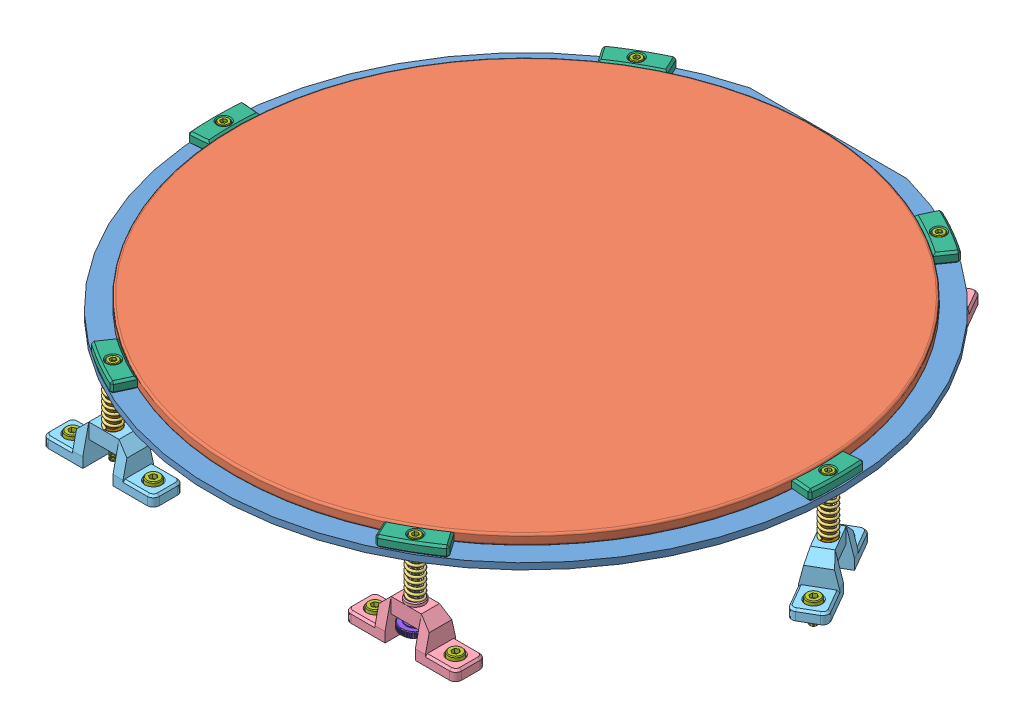
SolidWorks assembly Bed Assembly, configuration Default. Lengths in mm.
Overall size (340.49 52.35 312.47).
44 component instances, 9 part files, 98 mates.
Components (placement in the parent):
- Heat Bed-1: Heat Bed [Default] at origin size (310 3.1 305.01)
- Print Surface-1: Print Surface [Default] at (0 3.1 0) size (290 5.25 290)
- Bed Leveling Spring-1: Bed Leveling Spring [Default] at (150 -20 0) size (8.52 22.05 8.3)
- Bed Leveling Spring-2: Bed Leveling Spring [Default] at (75 -20 129.9038) size (8.52 22.05 8.3)
- Bed Leveling Spring-3: Bed Leveling Spring [Default] at (-75 -20 129.9038) size (8.52 22.05 8.3)
- Bed Leveling Spring-4: Bed Leveling Spring [Default] at (-150 -20 0) size (8.52 22.05 8.3)
- Bed Leveling Spring-5: Bed Leveling Spring [Default] at (-75 -20 -129.9038) size (8.52 22.05 8.3)
- Bed Leveling Spring-6: Bed Leveling Spring [Default] at (75 -20 -129.9038) size (8.52 22.05 8.3)
- Bed Foot-1: Bed Foot [Default] at (47.5 -38.5 122.4038) size (55 20.3 15)
- Bed Static Foot-2: Bed Static Foot [Default] at (-102.5 -38.5 122.4038) size (55 18.5 15)
- Bed Foot-3: Bed Foot [Default] at (82.2548 -38.5 -102.3381) x (-0.5 0 -0.866025) z (0.866025 0 -0.5) size (55 20.3 15)
- Bed Static Foot-4: Bed Static Foot [Default] at (-95.2452 -38.5 -109.8381) x (0.5 0 -0.866025) z (0.866025 0 0.5) size (55 18.5 15)
- Bed Foot-5: Bed Foot [Default] at (-170.2452 -38.5 20.0657) x (0.5 0 -0.866025) z (0.866025 0 0.5) size (55 20.3 15)
- Bed Static Foot-6: Bed Static Foot [Default] at (157.2548 -38.5 27.5657) x (-0.5 0 -0.866025) z (0.866025 0 -0.5) size (55 18.5 15)
- Print Surface Clip-1: Print Surface Clip [Default] at (0 3.1 0) x (0.866025 0 0.5) z (-0.5 0 0.866025) size (26.84 5.25 10.55)
- Print Surface Clip-2: Print Surface Clip [Default] at (0 3.1 0) x (0.866025 0 -0.5) z (0.5 0 0.866025) size (26.84 5.25 10.55)
- Print Surface Clip-3: Print Surface Clip [Default] at (0 3.1 0) x (0 0 -1) z (1 0 0) size (26.84 5.25 10.55)
- Print Surface Clip-4: Print Surface Clip [Default] at (0 3.1 0) x (-0.866025 0 -0.5) z (0.5 0 -0.866025) size (26.84 5.25 10.55)
- Print Surface Clip-5: Print Surface Clip [Default] at (0 3.1 0) x (-0.866025 0 0.5) z (-0.5 0 -0.866025) size (26.84 5.25 10.55)
- Print Surface Clip-6: Print Surface Clip [Default] at (0 3.1 0) x (0 0 1) z (-1 0 0) size (26.84 5.25 10.55)
- socket head cap screw_am-1: socket head cap screw_am [B18.3.1M - 3 x 0.5 x 40 Hex SHCS -- 40SHX] at (-150 8.35 0) x (0 -1 0) z (-0.546944 0 0.837169) size (43 5.5 5.5)
- socket head cap screw_am-2: socket head cap screw_am [B18.3.1M - 3 x 0.5 x 40 Hex SHCS -- 40SHX] at (-75 8.35 129.9038) x (0 -1 0) z (-0.546944 0 0.837169) size (43 5.5 5.5)
- socket head cap screw_am-3: socket head cap screw_am [B18.3.1M - 3 x 0.5 x 40 Hex SHCS -- 40SHX] at (75 8.35 129.9038) x (0 -1 0) z (-0.546944 0 0.837169) size (43 5.5 5.5)
- socket head cap screw_am-4: socket head cap screw_am [B18.3.1M - 3 x 0.5 x 40 Hex SHCS -- 40SHX] at (150 8.35 0) x (0 -1 0) z (-0.546944 0 0.837169) size (43 5.5 5.5)
- socket head cap screw_am-5: socket head cap screw_am [B18.3.1M - 3 x 0.5 x 40 Hex SHCS -- 40SHX] at (75 8.35 -129.9038) x (0 -1 0) z (-0.546944 0 0.837169) size (43 5.5 5.5)
- socket head cap screw_am-6: socket head cap screw_am [B18.3.1M - 3 x 0.5 x 40 Hex SHCS -- 40SHX] at (-75 8.35 -129.9038) x (0 -1 0) z (-0.546944 0 0.837169) size (43 5.5 5.5)
- Bed Leveling Knob-1: Bed Leveling Knob [Default] at (75 -32 129.9038) x (0 1 0) z (0 0 1) size (12 14 14)
- Bed Leveling Knob-3: Bed Leveling Knob [Default] at (75 -32 -129.9038) x (0 1 0) z (0 0 1) size (12 14 14)
- Bed Leveling Knob-5: Bed Leveling Knob [Default] at (-150 -32 0) x (0 1 0) z (0 0 1) size (12 14 14)
- socket head cap screw_am-7: socket head cap screw_am [B18.3.1M - 4 x 0.7 x 8 Hex SHCS -- 8SHX] at (-65 -32 -147.2243) x (0 -1 0) z (0 0 1) size (12 7 7)
- socket head cap screw_am-8: socket head cap screw_am [B18.3.1M - 4 x 0.7 x 8 Hex SHCS -- 8SHX] at (-85 -32 -112.5833) x (0 -1 0) z (-0.546944 0 0.837169) size (12 7 7)
- socket head cap screw_am-9: socket head cap screw_am [B18.3.1M - 4 x 0.7 x 8 Hex SHCS -- 8SHX] at (-140 -32 -17.3205) x (0 -1 0) z (-0.546944 0 0.837169) size (12 7 7)
- socket head cap screw_am-10: socket head cap screw_am [B18.3.1M - 4 x 0.7 x 8 Hex SHCS -- 8SHX] at (-160 -32 17.3205) x (0 -1 0) z (-0.546944 0 0.837169) size (12 7 7)
- socket head cap screw_am-11: socket head cap screw_am [B18.3.1M - 4 x 0.7 x 8 Hex SHCS -- 8SHX] at (65 -32 -147.2243) x (0 -1 0) z (-0.546944 0 0.837169) size (12 7 7)
- socket head cap screw_am-12: socket head cap screw_am [B18.3.1M - 4 x 0.7 x 8 Hex SHCS -- 8SHX] at (85 -32 -112.5833) x (0 -1 0) z (-0.546944 0 0.837169) size (12 7 7)
- socket head cap screw_am-13: socket head cap screw_am [B18.3.1M - 4 x 0.7 x 8 Hex SHCS -- 8SHX] at (140 -32 -17.3205) x (0 -1 0) z (-0.546944 0 0.837169) size (12 7 7)
- socket head cap screw_am-14: socket head cap screw_am [B18.3.1M - 4 x 0.7 x 8 Hex SHCS -- 8SHX] at (160 -32 17.3205) x (0 -1 0) z (-0.546944 0 0.837169) size (12 7 7)
- socket head cap screw_am-15: socket head cap screw_am [B18.3.1M - 4 x 0.7 x 8 Hex SHCS -- 8SHX] at (95 -32 129.9038) x (0 -1 0) z (-0.546944 0 0.837169) size (12 7 7)
- socket head cap screw_am-16: socket head cap screw_am [B18.3.1M - 4 x 0.7 x 8 Hex SHCS -- 8SHX] at (55 -32 129.9038) x (0 -1 0) z (-0.546944 0 0.837169) size (12 7 7)
- socket head cap screw_am-17: socket head cap screw_am [B18.3.1M - 4 x 0.7 x 8 Hex SHCS -- 8SHX] at (-55 -32 129.9038) x (0 -1 0) z (-0.546944 0 0.837169) size (12 7 7)
- socket head cap screw_am-18: socket head cap screw_am [B18.3.1M - 4 x 0.7 x 8 Hex SHCS -- 8SHX] at (-95 -32 129.9038) x (0 -1 0) z (-0.546944 0 0.837169) size (12 7 7)
- Surface Clip End Stop-1: Surface Clip End Stop [Default] at (-75 -28.5 -129.9038) size (7.7 20.5 7.7)
- Surface Clip End Stop-2: Surface Clip End Stop [Default] at (150 -28.5 0) size (7.7 20.5 7.7)
- Surface Clip End Stop-3: Surface Clip End Stop [Default] at (-75 -28.5 129.9038) size (7.7 20.5 7.7)
Mates (geometry in assembly coordinates):
- Coincident1: coincident: plane of Heat Bed-1 through (0 3.1 0) normal (0 1 0); plane of Print Surface-1 through (0 3.1 0) normal (0 -1 0)
- Concentric1: concentric: cylinder of Heat Bed-1 through (0 3.1 0) axis (0 -1 0) radius 155; cylinder of Print Surface-1 through (0 8.35 0) axis (0 -1 0) radius 145
- Concentric2: concentric: cylinder of Heat Bed-1 through (150 1.1 0) axis (0 1 0) radius 3.25; cylinder of Bed Leveling Spring-1 through (150 -21.2 0) axis (0 1 0) radius 2.95
- Concentric3: concentric: cylinder of Heat Bed-1 through (75 1.1 129.9038) axis (0 1 0) radius 3.25; cylinder of Bed Leveling Spring-2 through (75 -21.2 129.9038) axis (0 1 0) radius 2.95
- Concentric4: concentric: cylinder of Heat Bed-1 through (-75 1.1 129.9038) axis (0 1 0) radius 3.25; cylinder of Bed Leveling Spring-3 through (-75 -21.2 129.9038) axis (0 1 0) radius 2.95
- Concentric5: concentric: cylinder of Heat Bed-1 through (-150 1.1 0) axis (0 1 0) radius 3.25; cylinder of Bed Leveling Spring-4 through (-150 -21.2 0) axis (0 1 0) radius 2.95
- Concentric6: concentric: cylinder of Heat Bed-1 through (-75 1.1 -129.9038) axis (0 1 0) radius 3.25; cylinder of Bed Leveling Spring-5 through (-75 -21.2 -129.9038) axis (0 1 0) radius 2.95
- Concentric7: concentric: cylinder of Heat Bed-1 through (75 1.1 -129.9038) axis (0 1 0) radius 3.25; cylinder of Bed Leveling Spring-6 through (75 -21.2 -129.9038) axis (0 1 0) radius 2.95
- Coincident2: coincident: plane of Heat Bed-1 through (0 0 0) normal (0 -1 0); plane of Bed Leveling Spring-2 through (118 0 124.9038) normal (0 1 0)
- Coincident3: coincident: plane of Heat Bed-1 through (0 0 0) normal (0 -1 0); plane of Bed Leveling Spring-1 through (193 0 -5) normal (0 1 0)
- Coincident4: coincident: plane of Heat Bed-1 through (0 0 0) normal (0 -1 0); plane of Bed Leveling Spring-6 through (118 0 -134.9038) normal (0 1 0)
- Coincident5: coincident: plane of Heat Bed-1 through (0 0 0) normal (0 -1 0); plane of Bed Leveling Spring-5 through (-32 0 -134.9038) normal (0 1 0)
- Coincident6: coincident: plane of Heat Bed-1 through (0 0 0) normal (0 -1 0); plane of Bed Leveling Spring-4 through (-107 0 -5) normal (0 1 0)
- Coincident7: coincident: plane of Heat Bed-1 through (0 0 0) normal (0 -1 0); plane of Bed Leveling Spring-3 through (-32 0 124.9038) normal (0 1 0)
- Coincident8: coincident: plane of Bed Leveling Spring-1 through (107 -20 5) normal (0 -1 0); plane of Bed Static Foot-6 through (150.2452 -20 -14.5753) normal (0 1 0)
- Concentric8: concentric: cylinder of Bed Leveling Spring-1 through (150 -21.2 0) axis (0 1 0) radius 2.95; cylinder of Bed Static Foot-6 through (150 -39.8137 0) axis (0 1 0) radius 4
- Coincident9: coincident: plane of Bed Leveling Spring-4 through (-193 -20 5) normal (0 -1 0); plane of Bed Foot-5 through (-137.2548 -20 -7.0753) normal (0 1 0)
- Concentric9: concentric: cylinder of Bed Leveling Spring-4 through (-150 -21.2 0) axis (0 1 0) radius 2.95; cylinder of Bed Foot-5 through (-150 -37.6924 0) axis (0 1 0) radius 3.25
- Coincident12: coincident: plane of Bed Leveling Spring-2 through (32 -20 134.9038) normal (0 -1 0); plane of Bed Foot-1 through (87.5 -20 137.4038) normal (0 1 0)
- Concentric11: concentric: cylinder of Bed Leveling Spring-2 through (75 -21.2 129.9038) axis (0 1 0) radius 2.95; cylinder of Bed Foot-1 through (75 -37.6924 129.9038) axis (0 1 0) radius 3.25
- Coincident14: coincident: plane of Bed Leveling Spring-3 through (-118 -20 134.9038) normal (0 -1 0); plane of Bed Static Foot-2 through (-62.5 -20 137.4038) normal (0 1 0)
- Concentric10: concentric: cylinder of Bed Leveling Spring-3 through (-75 -21.2 129.9038) axis (0 1 0) radius 2.95; cylinder of Bed Static Foot-2 through (-75 -39.8137 129.9038) axis (0 1 0) radius 4
- Coincident18: coincident: plane of Bed Leveling Spring-6 through (32 -20 -124.9038) normal (0 -1 0); plane of Bed Foot-3 through (75.2452 -20 -144.4791) normal (0 1 0)
- Concentric12: concentric: cylinder of Bed Leveling Spring-6 through (75 -21.2 -129.9038) axis (0 1 0) radius 2.95; cylinder of Bed Foot-3 through (75 -37.6924 -129.9038) axis (0 1 0) radius 3.25
- Coincident20: coincident: plane of Bed Leveling Spring-5 through (-118 -20 -124.9038) normal (0 -1 0); plane of Bed Static Foot-4 through (-62.2548 -20 -136.9791) normal (0 1 0)
- Concentric13: concentric: cylinder of Bed Leveling Spring-5 through (-75 -21.2 -129.9038) axis (0 1 0) radius 2.95; cylinder of Bed Static Foot-4 through (-75 -39.8137 -129.9038) axis (0 1 0) radius 4
- Coincident23: coincident: plane of Bed Foot-1 through (47.5 -38.5 137.4038) normal (0 0 1); plane of Bed Static Foot-2 through (-102.5 -38.5 137.4038) normal (0 0 1)
- Coincident24: coincident: plane of Bed Foot-3 through (95.2452 -38.5 -109.8381) normal (0.866025 0 -0.5); plane of Bed Static Foot-6 through (170.2452 -38.5 20.0657) normal (0.866025 0 -0.5)
- Coincident25: coincident: plane of Bed Static Foot-4 through (-95.2452 -38.5 -109.8381) normal (-0.866025 0 -0.5); plane of Bed Foot-5 through (-170.2452 -38.5 20.0657) normal (-0.866025 0 -0.5)
- Concentric14: concentric: cylinder of Heat Bed-1 through (-75 1.1 129.9038) axis (0 1 0) radius 3.25; cylinder of Print Surface Clip-1 through (-75 5.35 129.9038) axis (0 1 0) radius 2.9
- Concentric15: concentric: cylinder of Heat Bed-1 through (75 1.1 129.9038) axis (0 1 0) radius 3.25; cylinder of Print Surface Clip-2 through (75 5.35 129.9038) axis (0 1 0) radius 2.9
- Concentric16: concentric: cylinder of Heat Bed-1 through (150 1.1 0) axis (0 1 0) radius 3.25; cylinder of Print Surface Clip-3 through (150 5.35 0) axis (0 1 0) radius 2.9
- Concentric17: concentric: cylinder of Heat Bed-1 through (75 1.1 -129.9038) axis (0 1 0) radius 3.25; cylinder of Print Surface Clip-4 through (75 5.35 -129.9038) axis (0 1 0) radius 2.9
- Concentric18: concentric: cylinder of Heat Bed-1 through (-75 1.1 -129.9038) axis (0 1 0) radius 3.25; cylinder of Print Surface Clip-5 through (-75 5.35 -129.9038) axis (0 1 0) radius 2.9
- Concentric19: concentric: cylinder of Heat Bed-1 through (-150 1.1 0) axis (0 1 0) radius 3.25; cylinder of Print Surface Clip-6 through (-150 5.35 0) axis (0 1 0) radius 2.9
- Coincident27: coincident: plane of Heat Bed-1 through (0 3.1 0) normal (0 1 0); plane of Print Surface Clip-1 through (0 3.1 0) normal (0 -1 0)
- Coincident28: coincident: plane of Heat Bed-1 through (0 3.1 0) normal (0 1 0); plane of Print Surface Clip-2 through (0 3.1 0) normal (0 -1 0)
- Coincident29: coincident: plane of Heat Bed-1 through (0 3.1 0) normal (0 1 0); plane of Print Surface Clip-3 through (0 3.1 0) normal (0 -1 0)
- Coincident30: coincident: plane of Heat Bed-1 through (0 3.1 0) normal (0 1 0); plane of Print Surface Clip-4 through (0 3.1 0) normal (0 -1 0)
- Coincident31: coincident: plane of Heat Bed-1 through (0 3.1 0) normal (0 1 0); plane of Print Surface Clip-5 through (0 3.1 0) normal (0 -1 0)
- Coincident32: coincident: plane of Heat Bed-1 through (0 3.1 0) normal (0 1 0); plane of Print Surface Clip-6 through (0 3.1 0) normal (0 -1 0)
- Concentric20: concentric: cylinder of Heat Bed-1 through (0 3.1 0) axis (0 -1 0) radius 155; cylinder of Print Surface Clip-2 through (0 8.35 0) axis (0 -1 0) radius 155
- Concentric21: concentric: cylinder of Heat Bed-1 through (0 3.1 0) axis (0 -1 0) radius 155; cylinder of Print Surface Clip-3 through (0 8.35 0) axis (0 -1 0) radius 155
- Concentric22: concentric: cylinder of Heat Bed-1 through (0 3.1 0) axis (0 -1 0) radius 155; cylinder of Print Surface Clip-4 through (0 8.35 0) axis (0 -1 0) radius 155
- Concentric23: concentric: cylinder of Heat Bed-1 through (0 3.1 0) axis (0 -1 0) radius 155; cylinder of Print Surface Clip-5 through (0 8.35 0) axis (0 -1 0) radius 155
- Concentric24: concentric: cylinder of Heat Bed-1 through (0 3.1 0) axis (0 -1 0) radius 155; cylinder of Print Surface Clip-6 through (0 8.35 0) axis (0 -1 0) radius 155
- Concentric25: concentric: cylinder of Heat Bed-1 through (0 3.1 0) axis (0 -1 0) radius 155; cylinder of Print Surface Clip-1 through (0 8.35 0) axis (0 -1 0) radius 155
- Concentric26: concentric: cylinder of Print Surface Clip-6 through (-150 5.35 0) axis (0 1 0) radius 2.9; cylinder of socket head cap screw_am-1 through (-150 40.1 0) axis (0 1 0) radius 2.75
- Concentric27: concentric: cylinder of Print Surface Clip-1 through (-75 5.35 129.9038) axis (0 1 0) radius 2.9; cylinder of socket head cap screw_am-2 through (-75 40.1 129.9038) axis (0 1 0) radius 2.75
- Concentric28: concentric: cylinder of Print Surface Clip-2 through (75 5.35 129.9038) axis (0 1 0) radius 2.9; cylinder of socket head cap screw_am-3 through (75 40.1 129.9038) axis (0 1 0) radius 2.75
- Concentric29: concentric: cylinder of Print Surface Clip-3 through (150 5.35 0) axis (0 1 0) radius 2.9; cylinder of socket head cap screw_am-4 through (150 40.1 0) axis (0 1 0) radius 2.75
- Concentric30: concentric: cylinder of Print Surface Clip-4 through (75 5.35 -129.9038) axis (0 1 0) radius 2.9; cylinder of socket head cap screw_am-5 through (75 40.1 -129.9038) axis (0 1 0) radius 2.75
- Concentric31: concentric: cylinder of Print Surface Clip-5 through (-75 5.35 -129.9038) axis (0 1 0) radius 2.9; cylinder of socket head cap screw_am-6 through (-75 40.1 -129.9038) axis (0 1 0) radius 2.75
- Coincident33: coincident: plane of Print Surface Clip-6 through (-150 5.35 0) normal (0 1 0); plane of socket head cap screw_am-1 through (-147.6978 5.35 1.5041) normal (0 -1 0)
- Coincident34: coincident: plane of Print Surface Clip-1 through (-75 5.35 129.9038) normal (0 1 0); plane of socket head cap screw_am-2 through (-72.6978 5.35 131.4079) normal (0 -1 0)
- Coincident35: coincident: plane of Print Surface Clip-2 through (75 5.35 129.9038) normal (0 1 0); plane of socket head cap screw_am-3 through (77.3022 5.35 131.4079) normal (0 -1 0)
- Coincident36: coincident: plane of Print Surface Clip-3 through (150 5.35 0) normal (0 1 0); plane of socket head cap screw_am-4 through (152.3022 5.35 1.5041) normal (0 -1 0)
- Coincident37: coincident: plane of Print Surface Clip-4 through (75 5.35 -129.9038) normal (0 1 0); plane of socket head cap screw_am-5 through (77.3022 5.35 -128.3997) normal (0 -1 0)
- Coincident38: coincident: plane of Print Surface Clip-5 through (-75 5.35 -129.9038) normal (0 1 0); plane of socket head cap screw_am-6 through (-72.6978 5.35 -128.3997) normal (0 -1 0)
- Concentric32: concentric: cylinder of socket head cap screw_am-3 through (75 40.1 129.9038) axis (0 1 0) radius 2.75; cylinder of Bed Leveling Knob-1 through (75 -48.1137 129.9038) axis (0 -1 0) radius 3
- Concentric33: concentric: cylinder of socket head cap screw_am-4 through (150 40.1 0) axis (0 1 0) radius 2.75; cylinder of ? through (150 -48.1137 0) axis (0 -1 0) radius 3
- Concentric34: concentric: cylinder of socket head cap screw_am-5 through (75 40.1 -129.9038) axis (0 1 0) radius 2.75; cylinder of Bed Leveling Knob-3 through (75 -48.1137 -129.9038) axis (0 -1 0) radius 3
- Concentric35: concentric: cylinder of socket head cap screw_am-6 through (-75 40.1 -129.9038) axis (0 1 0) radius 2.75; cylinder of ? through (-75 -48.1137 -129.9038) axis (0 -1 0) radius 3
- Concentric36: concentric: cylinder of socket head cap screw_am-1 through (-150 40.1 0) axis (0 1 0) radius 2.75; cylinder of Bed Leveling Knob-5 through (-150 -48.1137 0) axis (0 -1 0) radius 3
- Concentric37: concentric: cylinder of socket head cap screw_am-2 through (-75 40.1 129.9038) axis (0 1 0) radius 2.75; cylinder of ? through (-75 -48.1137 129.9038) axis (0 -1 0) radius 3
- Coincident39: coincident: plane of Bed Foot-1 through (67.5 -28.5 137.4038) normal (0 -1 0); plane of Bed Leveling Knob-1 through (72 -28.5 129.9038) normal (0 1 0)
- Coincident41: coincident: plane of Bed Foot-3 through (85.2452 -28.5 -127.1586) normal (0 -1 0); plane of Bed Leveling Knob-3 through (72 -28.5 -129.9038) normal (0 1 0)
- Coincident43: coincident: plane of Bed Foot-5 through (-147.2548 -28.5 10.2452) normal (0 -1 0); plane of Bed Leveling Knob-5 through (-153 -28.5 0) normal (0 1 0)
- Coincident45: coincident: plane of socket head cap screw_am-7 through (-61.5 -36 -147.2243) normal (0 -1 0); plane of socket head cap screw_am-8 through (-82.0699 -36 -110.669) normal (0 -1 0)
- Coincident46: coincident: plane of socket head cap screw_am-8 through (-82.0699 -36 -110.669) normal (0 -1 0); plane of socket head cap screw_am-9 through (-137.0699 -36 -15.4062) normal (0 -1 0)
- Coincident47: coincident: plane of socket head cap screw_am-9 through (-137.0699 -36 -15.4062) normal (0 -1 0); plane of socket head cap screw_am-10 through (-157.0699 -36 19.2348) normal (0 -1 0)
- Coincident48: coincident: plane of socket head cap screw_am-10 through (-157.0699 -36 19.2348) normal (0 -1 0); plane of socket head cap screw_am-11 through (67.9301 -36 -145.31) normal (0 -1 0)
- Coincident49: coincident: plane of socket head cap screw_am-11 through (67.9301 -36 -145.31) normal (0 -1 0); plane of socket head cap screw_am-12 through (87.9301 -36 -110.669) normal (0 -1 0)
- Coincident50: coincident: plane of socket head cap screw_am-12 through (87.9301 -36 -110.669) normal (0 -1 0); plane of socket head cap screw_am-13 through (142.9301 -36 -15.4062) normal (0 -1 0)
- Coincident51: coincident: plane of socket head cap screw_am-13 through (142.9301 -36 -15.4062) normal (0 -1 0); plane of socket head cap screw_am-14 through (162.9301 -36 19.2348) normal (0 -1 0)
- Coincident52: coincident: plane of socket head cap screw_am-14 through (162.9301 -36 19.2348) normal (0 -1 0); plane of socket head cap screw_am-15 through (97.9301 -36 131.8181) normal (0 -1 0)
- Coincident53: coincident: plane of socket head cap screw_am-15 through (97.9301 -36 131.8181) normal (0 -1 0); plane of socket head cap screw_am-16 through (57.9301 -36 131.8181) normal (0 -1 0)
- Coincident54: coincident: plane of socket head cap screw_am-16 through (57.9301 -36 131.8181) normal (0 -1 0); plane of socket head cap screw_am-17 through (-52.0699 -36 131.8181) normal (0 -1 0)
- Coincident55: coincident: plane of socket head cap screw_am-17 through (-52.0699 -36 131.8181) normal (0 -1 0); plane of socket head cap screw_am-18 through (-92.0699 -36 131.8181) normal (0 -1 0)
- Coincident56: coincident: plane of Bed Static Foot-2 through (-95 -36 129.9038) normal (0 1 0); plane of socket head cap screw_am-18 through (-92.0699 -36 131.8181) normal (0 -1 0)
- Concentric38: concentric: cylinder of Bed Static Foot-2 through (-95 -36 129.9038) axis (0 1 0) radius 3.65; cylinder of socket head cap screw_am-18 through (-95 -0.25 129.9038) axis (0 1 0) radius 3.5
- Concentric39: concentric: cylinder of socket head cap screw_am-17 through (-55 -0.25 129.9038) axis (0 1 0) radius 3.5; cylinder of Bed Static Foot-2 through (-55 -36 129.9038) axis (0 1 0) radius 3.65
- Concentric40: concentric: cylinder of Bed Foot-1 through (55 -36 129.9038) axis (0 1 0) radius 3.65; cylinder of socket head cap screw_am-16 through (55 -0.25 129.9038) axis (0 1 0) radius 3.5
- Concentric41: concentric: cylinder of Bed Foot-1 through (95 -36 129.9038) axis (0 1 0) radius 3.65; cylinder of socket head cap screw_am-15 through (95 -0.25 129.9038) axis (0 1 0) radius 3.5
- Concentric42: concentric: cylinder of Bed Static Foot-6 through (160 -36 17.3205) axis (0 1 0) radius 3.65; cylinder of socket head cap screw_am-14 through (160 -0.25 17.3205) axis (0 1 0) radius 3.5
- Concentric43: concentric: cylinder of Bed Static Foot-6 through (140 -36 -17.3205) axis (0 1 0) radius 3.65; cylinder of socket head cap screw_am-13 through (140 -0.25 -17.3205) axis (0 1 0) radius 3.5
- Concentric44: concentric: cylinder of Bed Foot-3 through (85 -36 -112.5833) axis (0 1 0) radius 3.65; cylinder of socket head cap screw_am-12 through (85 -0.25 -112.5833) axis (0 1 0) radius 3.5
- Concentric45: concentric: cylinder of Bed Foot-3 through (65 -36 -147.2243) axis (0 1 0) radius 3.65; cylinder of socket head cap screw_am-11 through (65 -0.25 -147.2243) axis (0 1 0) radius 3.5
- Concentric46: concentric: cylinder of Bed Static Foot-4 through (-65 -36 -147.2243) axis (0 1 0) radius 3.65; cylinder of socket head cap screw_am-7 through (-65 -0.25 -147.2243) axis (0 1 0) radius 3.5
- Concentric47: concentric: cylinder of Bed Static Foot-4 through (-85 -36 -112.5833) axis (0 1 0) radius 3.65; cylinder of socket head cap screw_am-8 through (-85 -0.25 -112.5833) axis (0 1 0) radius 3.5
- Concentric48: concentric: cylinder of Bed Foot-5 through (-140 -36 -17.3205) axis (0 1 0) radius 3.65; cylinder of socket head cap screw_am-9 through (-140 -0.25 -17.3205) axis (0 1 0) radius 3.5
- Concentric49: concentric: cylinder of Bed Foot-5 through (-160 -36 17.3205) axis (0 1 0) radius 3.65; cylinder of socket head cap screw_am-10 through (-160 -0.25 17.3205) axis (0 1 0) radius 3.5
- Coincident57: coincident: plane of Surface Clip End Stop-1 through (-72.6 -20 -129.9038) normal (0 1 0); plane of Surface Clip End Stop-2 through (152.4 -20 0) normal (0 1 0)
- Coincident58: coincident: plane of Surface Clip End Stop-2 through (152.4 -20 0) normal (0 1 0); plane of Surface Clip End Stop-3 through (-72.6 -20 129.9038) normal (0 1 0)
- Concentric50: concentric: cylinder of Bed Static Foot-2 through (-75 -39.8137 129.9038) axis (0 1 0) radius 4; cylinder of Surface Clip End Stop-3 through (-75 -18.7824 129.9038) axis (0 1 0) radius 2.4
- Concentric51: concentric: cylinder of Bed Static Foot-6 through (150 -39.8137 0) axis (0 1 0) radius 4; cylinder of Surface Clip End Stop-2 through (150 -18.7824 0) axis (0 1 0) radius 2.4
- Concentric52: concentric: cylinder of Bed Static Foot-4 through (-75 -39.8137 -129.9038) axis (0 1 0) radius 4; cylinder of Surface Clip End Stop-1 through (-75 -18.7824 -129.9038) axis (0 1 0) radius 2.4
- Coincident60: coincident: plane of Bed Leveling Spring-1 through (107 -20 5) normal (0 -1 0); plane of Surface Clip End Stop-2 through (152.4 -20 0) normal (0 1 0)
